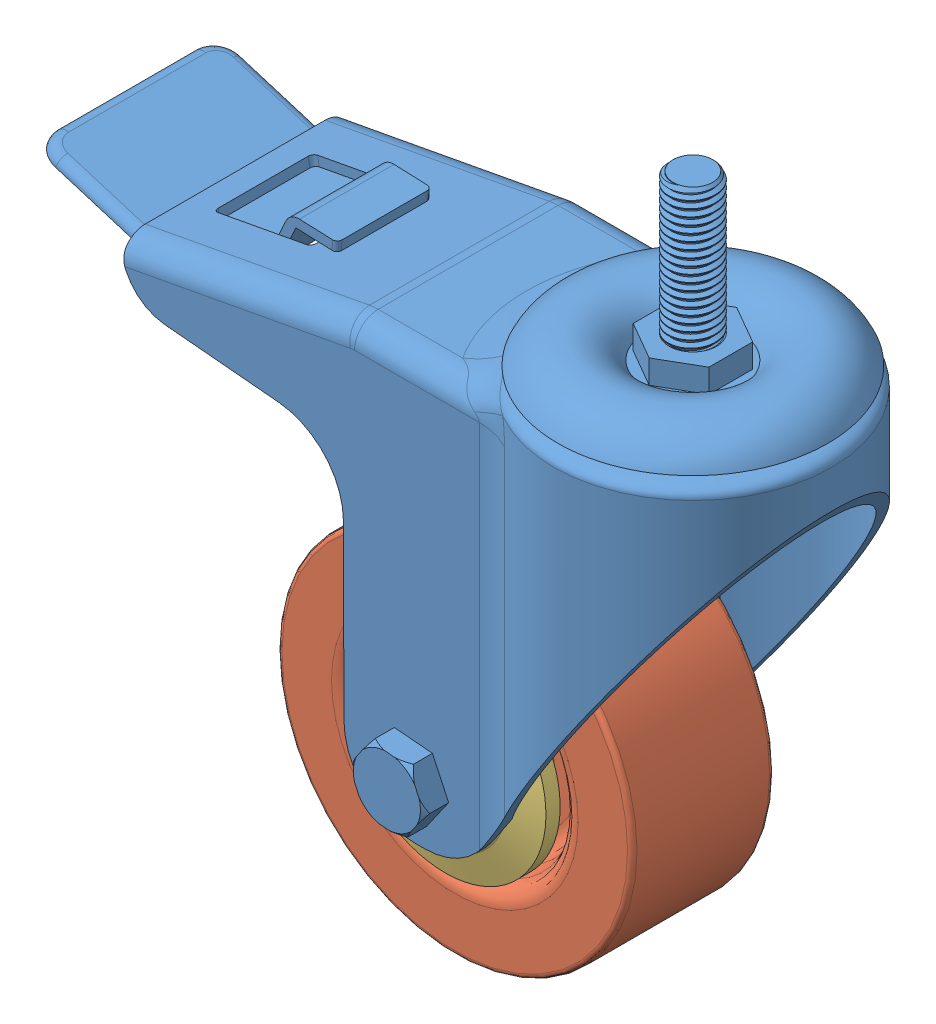
SolidWorks assembly AL-SCtkb93.10 Модель2, configuration По умолчанию. Lengths in mm.
Overall size (151.63 154.33 64.15).
4 component instances, 3 part files, 5 mates.
Components (placement in the parent):
- Деталь-1: Деталь [По умолчанию] at origin size (151.63 128.83 64.15)
- Деталь - колесо-2: Деталь - колесо [По умолчанию] at (0 0 -8.6954) size (75 75 30.01)
- Кусок3-1: Кусок3 [По умолчанию] at (3.9442 -3.1814 -8.8454) x (0.997483 -0.070903 0) z (0 0 1) size (42.5 42.5 8)
- Кусок3-2: Кусок3 [По умолчанию] at (-113.7271 -48.4079 8.4826) x (-0.693225 -0.720721 0) z (0 0 -1) size (42.5 42.5 8)
Mates (geometry in assembly coordinates):
- Концентричный16: concentric anti-aligned: cylinder of Деталь - колесо-2 through (-42.8409 -57.1481 -15.1814) axis (0 0 1) radius 11; circle of Кусок3-2
- Концентричный17: concentric aligned: cylinder of Деталь - колесо-2 through (-42.8409 -57.1481 -15.1814) axis (0 0 1) radius 11; circle of Кусок3-1
- Концентричный23: concentric aligned: cylinder of Деталь-1 through (-42.8409 -57.1481 -25.836) axis (0 0 1) radius 4; cylinder of Деталь - колесо-2 through (-42.8409 -57.1481 -15.1814) axis (0 0 1) radius 11
- Совпадение18: coincident anti-aligned: plane of Деталь-1 through (-24.4499 -69.1481 21.8186) normal (0 0 -1); plane of Кусок3-2 through (-42.8409 -57.1481 21.8186) normal (0 0 1)
- Совпадение23: coincident anti-aligned: plane of Деталь-1 through (-24.4499 -69.1481 -22.1814) normal (0 0 1); plane of Кусок3-1 through (-42.8409 -57.1481 -22.1814) normal (0 0 -1)
